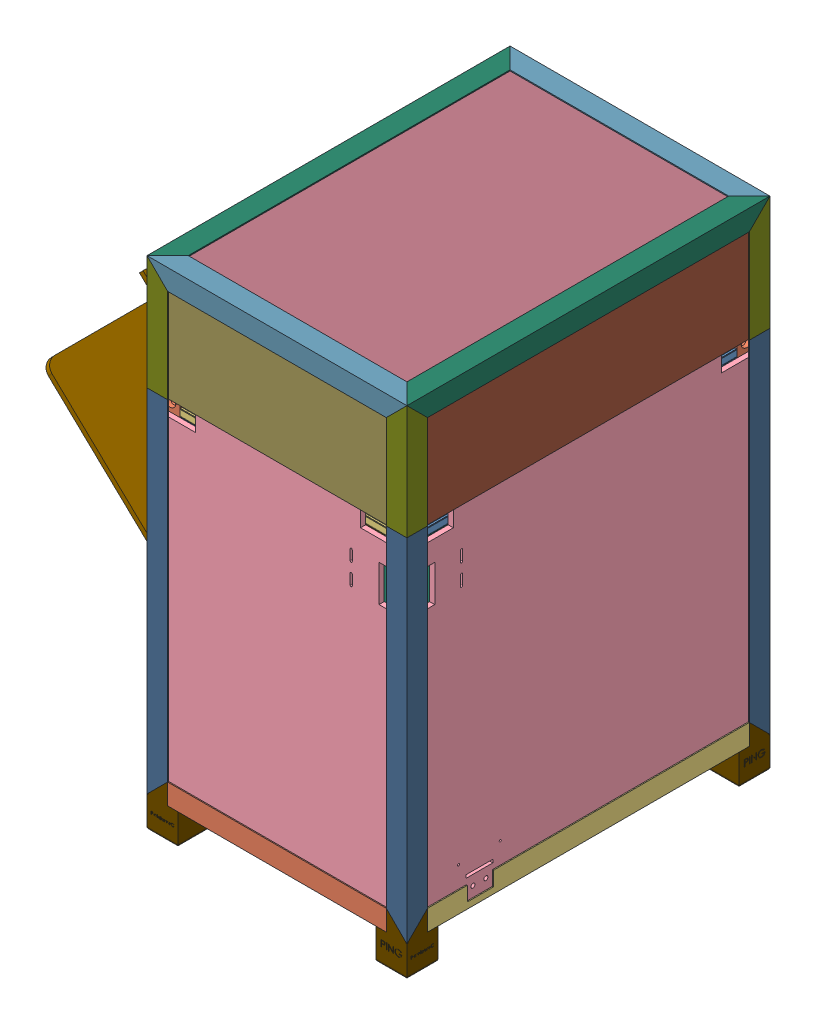
SolidWorks assembly carcasse, configuration Défaut. Lengths in mm.
Overall size (850.58 964 704).
62 component instances, 25 part files, 73 mates.
Components (placement in the parent):
- cadre_600x300mm-1: cadre_600x300mm [Défaut] at (-215.194 -19.8636 -400) size (480 40 680)
  - prof_40x40x600mm-1: prof_40x40x600mm [Défaut] at (-14.8937 4.0689 600) size (40 40 600)
  - Rexroth-Default-1: Rexroth-Default [Default] at (-14.8937 24.0689 720) x (0 -1 0) z (-1 0 0) size (40 40 40)
  - prof_40x40x600mm-3: prof_40x40x600mm [Défaut] at (425.1063 4.0689 600) size (40 40 600)
  - Rexroth-Default-3: Rexroth-Default [Default] at (-14.8937 24.0689 80) x (0 -1 0) z (0 0 -1) size (40 40 40)
  - Rexroth-Default-4: Rexroth-Default [Default] at (425.1063 24.0689 80) x (0 -1 0) z (1 0 0) size (40 40 40)
  - Rexroth-Default-5: Rexroth-Default [Default] at (425.1063 24.0689 720) x (0 -1 0) z (0 0 1) size (40 40 40)
  - prof_40x40x300mm-1: prof_40x40x300mm [Défaut] at (105.1063 4.0689 720) x (0 0 1) z (-1 0 0) size (40 40 400)
  - prof_40x40x300mm-2: prof_40x40x300mm [Défaut] at (105.1063 4.0689 80) x (0 0 1) z (-1 0 0) size (40 40 400)
- prof_40x40x600mm-1: prof_40x40x600mm [Défaut] at (209.9123 104.2053 -320) x (1 0 0) z (0 -1 0) size (40 40 600)
- prof_40x40x600mm-2: prof_40x40x600mm [Défaut] at (209.9123 104.2053 320) x (1 0 0) z (0 -1 0) size (40 40 600)
- prof_40x40x600mm-3: prof_40x40x600mm [Défaut] at (-230.0877 104.2053 320) x (1 0 0) z (0 -1 0) size (40 40 600)
- prof_40x40x600mm-4: prof_40x40x600mm [Défaut] at (-230.0877 104.2053 -320) x (1 0 0) z (0 -1 0) size (40 40 600)
- cadre_600x300mm-2: cadre_600x300mm [Défaut] at (195.0186 628.2742 -400) x (-1 0 0) z (0 0 1) size (480 40 680)
  - prof_40x40x600mm-1: prof_40x40x600mm [Défaut] at (-14.8937 4.0689 600) size (40 40 600)
  - Rexroth-Default-1: Rexroth-Default [Default] at (-14.8937 24.0689 720) x (0 -1 0) z (-1 0 0) size (40 40 40)
  - prof_40x40x600mm-3: prof_40x40x600mm [Défaut] at (425.1063 4.0689 600) size (40 40 600)
  - Rexroth-Default-3: Rexroth-Default [Default] at (-14.8937 24.0689 80) x (0 -1 0) z (0 0 -1) size (40 40 40)
  - Rexroth-Default-4: Rexroth-Default [Default] at (425.1063 24.0689 80) x (0 -1 0) z (1 0 0) size (40 40 40)
  - Rexroth-Default-5: Rexroth-Default [Default] at (425.1063 24.0689 720) x (0 -1 0) z (0 0 1) size (40 40 40)
  - prof_40x40x300mm-1: prof_40x40x300mm [Défaut] at (105.1063 4.0689 720) x (0 0 1) z (-1 0 0) size (40 40 400)
  - prof_40x40x300mm-2: prof_40x40x300mm [Défaut] at (105.1063 4.0689 80) x (0 0 1) z (-1 0 0) size (40 40 400)
- plaque_acrylique_680x670-2: plaque_acrylique_680x670 [Défaut] at (229.9123 299.2053 0) x (0 0 -1) z (1 0 0) size (680 670 10)
- plaque_acrylique_380x670_G-1: plaque_acrylique_380x670_G [Défaut] at (39.9123 299.2053 -350) size (480 670 10)
- plaque_acrylique_680x670_porte-1: plaque_acrylique_680x670_porte [Défaut] at (-260.0877 299.2053 0) x (0 0 -1) z (1 0 0) size (680 670 10)
- charniere-1: charniere [Défaut] at (-253.7309 154.2053 256.2875) x (0 0 1) z (0 -1 0) size (40 29.08 53.23)
  - axe charnière-1: axe charnière [Défaut] at (-76.2875 9.8568 0) size (40 5 5)
  - batant charnière-1: batant charnière [Défaut] at (-76.2875 10.1991 -17.6196) size (40 7 33.5)
  - batant charnière-2: batant charnière [Défaut] at (-36.2875 -2.6626 12.4029) x (-1 0 0) z (0 0.723942 -0.689861) size (40 7 33.5)
- charniere-2: charniere [Défaut] at (-253.7309 154.2053 -143.7125) x (0 0 1) z (0 -1 0) size (40 29.08 53.23)
  - axe charnière-1: axe charnière [Défaut] at (-76.2875 9.8568 0) size (40 5 5)
  - batant charnière-1: batant charnière [Défaut] at (-76.2875 10.1991 -17.6196) size (40 7 33.5)
  - batant charnière-2: batant charnière [Défaut] at (-36.2875 -2.6626 12.4029) x (-1 0 0) z (0 0.723942 -0.689861) size (40 7 33.5)
- porte-1: porte [Défaut] at (-366.1448 256.769 0) x (0 0 -1) z (0.689861 0.723942 0) size (480 480 10)
- eclisse_40x40x670_bisote_x1-1: eclisse_40x40x670_bisote_x1 [Défaut] at (-242.0877 -47.7947 -331.8864) size (40 682 40)
- eclisse_40x40x670_bisote_x1-2: eclisse_40x40x670_bisote_x1 [Défaut] at (-241.9741 -47.7947 332) x (0 0 -1) z (1 0 0) size (40 682 40)
- eclisse_40x40x670_bisote_x1-3: eclisse_40x40x670_bisote_x1 [Défaut] at (221.9123 -47.7947 331.8864) x (-1 0 0) z (0 0 -1) size (40 682 40)
- eclisse_40x40x670_bisote_x1-4: eclisse_40x40x670_bisote_x1 [Défaut] at (221.7986 -47.7947 -332) x (0 0 1) z (-1 0 0) size (40 682 40)
- couvercle-1: couvercle [Défaut] at (227.4119 747.9268 345) size (504 222 704)
  - plaque_acrylique_680x210-2: plaque_acrylique_680x210 [Défaut] at (-487.4996 -8.7215 -345) x (0 0 -1) z (1 0 0) size (680 210 10)
  - plaque_acrylique_380x210-2: plaque_acrylique_380x210 [Défaut] at (-187.4996 -8.7215 -695) size (480 210 10)
  - plaque_acrylique_380x680-1: plaque_acrylique_380x680 [Défaut] at (-187.4996 96.2785 -345) x (1 0 0) z (0 1 0) size (480 680 10)
  - eclisse_40x40x404_bisote_x2-1: eclisse_40x40x404_bisote_x2 [Défaut] at (14.5004 88.1649 -677) x (0 0 1) z (0 -1 0) size (40 504 40)
  - eclisse_40x40x704_bisote_x2-1: eclisse_40x40x704_bisote_x2 [Défaut] at (-5.6132 88.2785 -697) x (0 -1 0) z (-1 0 0) size (40 704 40)
  - eclisse_40x40x404_bisote_x2-2: eclisse_40x40x404_bisote_x2 [Défaut] at (-489.4996 88.1649 -13) x (0 0 -1) z (0 -1 0) size (40 504 40)
  - eclisse_40x40x704_bisote_x2-2: eclisse_40x40x704_bisote_x2 [Défaut] at (-469.4996 88.1649 -697) x (1 0 0) z (0 -1 0) size (40 704 40)
  - eclisse_40x40x222_bisote_x1-1: eclisse_40x40x222_bisote_x1 [Défaut] at (-469.386 108.2785 -677) x (0 0 1) z (1 0 0) size (40 222 40)
  - eclisse_40x40x222_bisote_x1-2: eclisse_40x40x222_bisote_x1 [Défaut] at (-5.4996 108.2785 -676.8864) x (-1 0 0) z (0 0 1) size (40 222 40)
  - eclisse_40x40x222_bisote_x1-4: eclisse_40x40x222_bisote_x1 [Défaut] at (-469.4996 108.2785 -13.1136) x (1 0 0) z (0 0 -1) size (40 222 40)
  - plaque_acrylique_380x210_Moteur-1: plaque_acrylique_380x210_Moteur [Défaut] at (-187.4996 -8.7215 -5) size (480 210 10)
  - plaque_acrylique_680x210_Moteur-1: plaque_acrylique_680x210_Moteur [Défaut] at (2.5004 -8.7215 -345) x (0 0 -1) z (1 0 0) size (680 210 10)
  - eclisse_40x40x222_bisote_x1_Moteur-1: eclisse_40x40x222_bisote_x1_Moteur [Défaut] at (-5.6132 108.2785 -13) x (0 0 -1) z (-1 0 0) size (40 222 40)
- plaque_acrylique_bas_380x680-1: plaque_acrylique_bas_380x680 [Défaut] at (39.9123 -35.7947 0) x (1 0 0) z (0 -1 0) size (480 680 10)
- Pied-1: Pied [Défaut] at (181.9123 -47.7947 -292) x (-1 0 0) z (0 -1 0) size (60 60 100)
- Pied-2: Pied [Défaut] at (181.9123 -47.7947 292) x (0 0 -1) z (0 -1 0) size (60 60 100)
- Pied-3: Pied [Défaut] at (-202.0877 -47.7947 292) x (1 0 0) z (0 -1 0) size (60 60 100)
- Pied-4: Pied [Défaut] at (-202.0877 -47.7947 -292) x (0 0 1) z (0 -1 0) size (60 60 100)
- eclisse_bas_40x40x704-2: eclisse_bas_40x40x704 [Défaut] at (-242.0877 -27.681 312) x (1 0 0) z (0 1 0) size (40 624 40)
- eclisse_bas_40x40x404-1: eclisse_bas_40x40x404 [Défaut] at (-222.0877 -27.681 -332) x (0 0 1) z (0 1 0) size (40 424 40)
- eclisse_bas_40x40x404-2: eclisse_bas_40x40x404 [Défaut] at (201.9123 -27.681 332) x (0 0 -1) z (0 1 0) size (40 424 40)
- eclisse_bas_support_Z_40x40x704-1: eclisse_bas_support_Z_40x40x704 [Défaut] at (221.7986 -27.7947 312) x (0 1 0) z (-1 0 0) size (40 624 40)
- plaque_acrylique_380x670_D-2: plaque_acrylique_380x670_D [Défaut] at (-60.0877 299.2053 350) x (-1 0 0) z (0 0 -1) size (480 670 10)
Mates (geometry in assembly coordinates):
- Coïncidente1: coincident anti-aligned: plane of cadre_600x300mm-1/Rexroth-Default-3 through (-230.0877 4.2053 -320) normal (0 1 0); plane of prof_40x40x600mm-4 through (-213.0877 4.2053 -337) normal (0 -1 0)
- Coïncidente2: coincident anti-aligned: plane of cadre_600x300mm-1/Rexroth-Default-1 through (-230.0877 4.2053 320) normal (0 1 0); plane of prof_40x40x600mm-3 through (-213.0877 4.2053 303) normal (0 -1 0)
- Coïncidente3: coincident anti-aligned: plane of cadre_600x300mm-1/Rexroth-Default-5 through (209.9123 4.2053 320) normal (0 1 0); plane of prof_40x40x600mm-2 through (226.9123 4.2053 303) normal (0 -1 0)
- Coïncidente4: coincident anti-aligned: plane of cadre_600x300mm-1/Rexroth-Default-4 through (209.9123 4.2053 -320) normal (0 1 0); plane of prof_40x40x600mm-1 through (226.9123 4.2053 -337) normal (0 -1 0)
- Coïncidente5: coincident aligned: plane of cadre_600x300mm-1/Rexroth-Default-4 through (229.9123 -15.7947 -320) normal (1 0 0); plane of prof_40x40x600mm-1 through (229.9123 604.2053 -314) normal (1 0 0)
- Coïncidente6: coincident aligned: plane of cadre_600x300mm-1/Rexroth-Default-4 through (209.9123 -15.7947 -340) normal (0 0 -1); plane of prof_40x40x600mm-1 through (215.9123 604.2053 -340) normal (0 0 -1)
- Coïncidente7: coincident aligned: plane of cadre_600x300mm-1/Rexroth-Default-5 through (229.9123 -15.7947 320) normal (1 0 0); plane of prof_40x40x600mm-2 through (229.9123 604.2053 303) normal (1 0 0)
- Coïncidente8: coincident aligned: plane of cadre_600x300mm-1/Rexroth-Default-5 through (209.9123 -15.7947 340) normal (0 0 1); plane of prof_40x40x600mm-2 through (226.9123 604.2053 340) normal (0 0 1)
- Coïncidente9: coincident aligned: plane of cadre_600x300mm-1/Rexroth-Default-1 through (-230.0877 -15.7947 340) normal (0 0 1); plane of prof_40x40x600mm-3 through (-213.0877 604.2053 340) normal (0 0 1)
- Coïncidente10: coincident aligned: plane of cadre_600x300mm-1/Rexroth-Default-1 through (-250.0877 -15.7947 320) normal (-1 0 0); plane of prof_40x40x600mm-3 through (-250.0877 604.2053 337) normal (-1 0 0)
- Coïncidente11: coincident aligned: plane of cadre_600x300mm-1/Rexroth-Default-3 through (-250.0877 -15.7947 -320) normal (-1 0 0); plane of prof_40x40x600mm-4 through (-250.0877 604.2053 -303) normal (-1 0 0)
- Coïncidente12: coincident aligned: plane of cadre_600x300mm-1/Rexroth-Default-3 through (-230.0877 -15.7947 -340) normal (0 0 -1); plane of prof_40x40x600mm-4 through (-247.0877 604.2053 -340) normal (0 0 -1)
- Coïncidente13: coincident anti-aligned: plane of prof_40x40x600mm-1 through (226.9123 604.2053 -337) normal (0 1 0); plane of cadre_600x300mm-2/Rexroth-Default-3 through (209.9123 604.2053 -320) normal (0 -1 0)
- Coïncidente14: coincident aligned: plane of prof_40x40x600mm-3 through (-250.0877 604.2053 337) normal (-1 0 0); plane of cadre_600x300mm-2/Rexroth-Default-5 through (-250.0877 624.2053 320) normal (-1 0 0)
- Coïncidente15: coincident aligned: plane of prof_40x40x600mm-3 through (-236.0877 604.2053 340) normal (0 0 1); plane of cadre_600x300mm-2/Rexroth-Default-5 through (-230.0877 624.2053 340) normal (0 0 1)
- Coïncidente38: coincident anti-aligned: plane of cadre_600x300mm-2/prof_40x40x600mm-1 through (229.9123 630.2053 -300) normal (1 0 0); plane of plaque_acrylique_680x670-2 through (229.9123 299.2053 0) normal (-1 0 0)
- Coïncidente39: coincident aligned: plane of prof_40x40x600mm-2 through (226.9123 604.2053 340) normal (0 0 1); plane of plaque_acrylique_680x670-2 through (239.9123 634.2053 340) normal (0 0 1)
- Coïncidente40: coincident aligned: plane of cadre_600x300mm-1/prof_40x40x600mm-3 through (215.9123 -35.7947 -300) normal (0 -1 0); plane of plaque_acrylique_680x670-2 through (239.9123 -35.7947 340) normal (0 -1 0)
- Coïncidente44: coincident aligned: plane of cadre_600x300mm-1/prof_40x40x300mm-2 through (189.9123 -35.7947 -337) normal (0 -1 0); plane of plaque_acrylique_380x670_G-1 through (-250.0877 -35.7947 -340) normal (0 -1 0)
- Coïncidente45: coincident aligned: plane of cadre_600x300mm-2/Rexroth-Default-4 through (-250.0877 624.2053 -320) normal (-1 0 0); plane of plaque_acrylique_380x670_G-1 through (-250.0877 634.2053 -340) normal (-1 0 0)
- Coïncidente46: coincident anti-aligned: plane of prof_40x40x600mm-4 through (-247.0877 604.2053 -340) normal (0 0 -1); plane of plaque_acrylique_380x670_G-1 through (39.9123 299.2053 -340) normal (0 0 1)
- Coïncidente48: coincident aligned: plane of cadre_600x300mm-2/Rexroth-Default-5 through (-230.0877 624.2053 340) normal (0 0 1); plane of plaque_acrylique_680x670_porte-1 through (-250.0877 634.2053 340) normal (0 0 1)
- Coïncidente50: coincident anti-aligned: plane of plaque_acrylique_680x670_porte-1 through (-260.0877 299.2053 0) normal (-1 0 0); plane of charniere-1/batant charnière-1 through (-260.0877 114.2053 220) normal (1 0 0)
- Coïncidente51: coincident anti-aligned: plane of plaque_acrylique_680x670_porte-1 through (-260.0877 299.2053 0) normal (-1 0 0); plane of charniere-2/batant charnière-1 through (-260.0877 114.2053 -180) normal (1 0 0)
- Distance4: distance = 20 mm anti-aligned: plane of charniere-2/batant charnière-1 through (-263.5877 154.2053 -220) normal (0 0 -1); plane of plaque_acrylique_680x670_porte-1 through (-260.0877 574.2053 -240) normal (0 0 1)
- Coïncidente54: coincident aligned: line of plaque_acrylique_680x670_porte-1 through (-260.0877 154.2053 220) axis (0 0 -1); line of charniere-2/batant charnière-1 through (-260.0877 154.2053 -180) axis (0 0 -1)
- Distance5: distance = 20 mm anti-aligned: plane of plaque_acrylique_680x670_porte-1 through (-260.0877 574.2053 240) normal (0 0 -1); plane of charniere-1/batant charnière-1 through (-263.5877 154.2053 220) normal (0 0 1)
- Coïncidente57: coincident aligned: line of plaque_acrylique_680x670_porte-1 through (-260.0877 154.2053 220) axis (0 0 -1); line of charniere-1/batant charnière-1 through (-260.0877 154.2053 220) axis (0 0 -1)
- Coïncidente62: coincident anti-aligned: plane of charniere-1/batant charnière-2 through (-290.1309 184.3336 180) normal (0.689861 0.723942 0); plane of porte-1 through (-586.947 467.1766 30) normal (-0.689861 -0.723942 0)
- Coïncidente63: coincident anti-aligned: line of charniere-1/batant charnière-2 through (-261.1732 156.7391 200) axis (0 0 1); line of porte-1 through (-261.1732 156.7391 220) axis (0 0 -1)
- Coïncidente64: coincident anti-aligned: plane of plaque_acrylique_680x670_porte-1 through (-260.0877 574.2053 240) normal (0 0 -1); plane of porte-1 through (-558.3301 453.7202 240) normal (0 0 1)
- Coïncidente65: coincident anti-aligned: plane of plaque_acrylique_380x670_G-1 through (39.9123 299.2053 -350) normal (0 0 -1); plane of eclisse_40x40x670_bisote_x1-1 through (-260.0877 634.2053 -350) normal (0 0 1)
- Coïncidente66: coincident anti-aligned: plane of plaque_acrylique_680x670_porte-1 through (-260.0877 299.2053 0) normal (-1 0 0); plane of eclisse_40x40x670_bisote_x1-1 through (-260.0877 634.2053 -350) normal (1 0 0)
- Coïncidente67: coincident aligned: plane of plaque_acrylique_680x670_porte-1 through (-250.0877 634.2053 340) normal (0 1 0); plane of eclisse_40x40x670_bisote_x1-1 through (-242.0877 634.2053 -331.8864) normal (0 1 0)
- Coïncidente68: coincident anti-aligned: plane of plaque_acrylique_680x670-2 through (239.9123 299.2053 0) normal (1 0 0); plane of eclisse_40x40x670_bisote_x1-4 through (239.9123 634.2053 -350) normal (-1 0 0)
- Coïncidente69: coincident anti-aligned: plane of plaque_acrylique_380x670_G-1 through (39.9123 299.2053 -350) normal (0 0 -1); plane of eclisse_40x40x670_bisote_x1-4 through (239.9123 634.2053 -350) normal (0 0 1)
- Coïncidente70: coincident aligned: plane of plaque_acrylique_380x670_G-1 through (-250.0877 634.2053 -340) normal (0 1 0); plane of eclisse_40x40x670_bisote_x1-4 through (221.7986 634.2053 -332) normal (0 1 0)
- Coïncidente72: coincident anti-aligned: plane of plaque_acrylique_680x670_porte-1 through (-260.0877 299.2053 0) normal (-1 0 0); plane of eclisse_40x40x670_bisote_x1-2 through (-260.0877 634.2053 350) normal (1 0 0)
- Coïncidente74: coincident anti-aligned: plane of plaque_acrylique_680x670-2 through (239.9123 299.2053 0) normal (1 0 0); plane of eclisse_40x40x670_bisote_x1-3 through (239.9123 634.2053 350) normal (-1 0 0)
- Coïncidente100: coincident: plane of plaque_acrylique_680x670_porte-1 through (-250.0877 634.2053 340) normal (0 1 0); line of eclisse_40x40x670_bisote_x1-2 through (-260.0877 634.2053 350) axis (0 0 -1)
- Coïncidente101: coincident anti-aligned: plane of prof_40x40x600mm-4 through (-250.0877 604.2053 -326) normal (-1 0 0); plane of plaque_acrylique_680x670_porte-1 through (-250.0877 299.2053 0) normal (1 0 0)
- Coïncidente116: coincident anti-aligned: line of plaque_acrylique_680x670-2 through (239.9123 634.2053 -260) axis (0 0 1); line of couvercle-1/plaque_acrylique_680x210_Moteur-1 through (239.9123 634.2053 340) axis (0 0 -1)
- Coïncidente117: coincident anti-aligned: line of plaque_acrylique_380x670_G-1 through (149.9123 634.2053 -350) axis (-1 0 0); line of couvercle-1/plaque_acrylique_380x210-2 through (-170.0877 634.2053 -350) axis (1 0 0)
- Coïncidente118: coincident anti-aligned: plane of cadre_600x300mm-1/prof_40x40x600mm-1 through (-247.0877 -35.7947 -300) normal (0 -1 0); plane of plaque_acrylique_bas_380x680-1 through (39.9123 -35.7947 0) normal (0 1 0)
- Coïncidente119: coincident: plane of cadre_600x300mm-1/prof_40x40x600mm-1 through (-250.0877 -21.7947 -300) normal (-1 0 0); line of plaque_acrylique_bas_380x680-1 through (-250.0877 -35.7947 340) axis (0 0 -1)
- Coïncidente120: coincident: line of cadre_600x300mm-1/prof_40x40x300mm-2 through (189.9123 -32.7947 -340) axis (-1 0 0); plane of plaque_acrylique_bas_380x680-1 through (-250.0877 -45.7947 -340) normal (0 0 -1)
- Coaxiale1: concentric aligned: cylinder of plaque_acrylique_bas_380x680-1 through (209.9123 -35.7947 -320) axis (0 -1 0) radius 12.5; cylinder of Pied-1 through (209.9123 -27.7947 -320) axis (0 -1 0) radius 12
- Coïncidente124: coincident anti-aligned: plane of eclisse_40x40x670_bisote_x1-4 through (-348.0877 -47.7947 -352) normal (0 -0.707107 0.707107); plane of Pied-1 through (239.9123 -7.7947 -312) normal (0 0.707107 -0.707107)
- Coaxiale2: concentric aligned: circle of plaque_acrylique_bas_380x680-1; cylinder of Pied-2 through (209.9123 -27.7947 320) axis (0 -1 0) radius 12
- Coïncidente126: coincident anti-aligned: plane of eclisse_40x40x670_bisote_x1-3 through (241.9123 -47.7947 -238) normal (-0.707107 -0.707107 0); plane of Pied-2 through (201.9123 -7.7947 350) normal (0.707107 0.707107 0)
- Coaxiale3: concentric aligned: circle of plaque_acrylique_bas_380x680-1; cylinder of Pied-3 through (-230.0877 -27.7947 320) axis (0 -1 0) radius 12
- Coïncidente130: coincident anti-aligned: plane of eclisse_40x40x670_bisote_x1-2 through (327.9123 -47.7947 352) normal (0 -0.707107 -0.707107); plane of Pied-3 through (-260.0877 -7.7947 312) normal (0 0.707107 0.707107)
- Coaxiale4: concentric aligned: circle of plaque_acrylique_bas_380x680-1; cylinder of Pied-4 through (-230.0877 -27.7947 -320) axis (0 -1 0) radius 12
- Coïncidente131: coincident anti-aligned: plane of eclisse_40x40x670_bisote_x1-1 through (-262.0877 -47.7947 238) normal (0.707107 -0.707107 0); plane of Pied-4 through (-222.0877 -7.7947 -350) normal (-0.707107 0.707107 0)
- Coïncidente132: coincident anti-aligned: plane of plaque_acrylique_680x670_porte-1 through (-260.0877 299.2053 0) normal (-1 0 0); plane of eclisse_bas_40x40x704-2 through (-260.0877 -45.7947 -312) normal (1 0 0)
- Coïncidente133: coincident anti-aligned: plane of plaque_acrylique_bas_380x680-1 through (39.9123 -45.7947 0) normal (0 -1 0); plane of eclisse_bas_40x40x704-2 through (-260.0877 -45.7947 -312) normal (0 1 0)
- Coïncidente134: coincident anti-aligned: line of eclisse_40x40x670_bisote_x1-2 through (-262.0877 634.2053 312) axis (0 -1 0); line of eclisse_bas_40x40x704-2 through (-262.0877 -47.7947 312) axis (0 1 0)
- Coïncidente135: coincident anti-aligned: plane of plaque_acrylique_380x670_G-1 through (39.9123 299.2053 -350) normal (0 0 -1); plane of eclisse_bas_40x40x404-1 through (201.9123 -45.7947 -350) normal (0 0 1)
- Coïncidente136: coincident anti-aligned: plane of plaque_acrylique_bas_380x680-1 through (39.9123 -45.7947 0) normal (0 -1 0); plane of eclisse_bas_40x40x404-1 through (201.9123 -45.7947 -350) normal (0 1 0)
- Coïncidente137: coincident anti-aligned: line of Pied-1 through (201.9123 -7.7947 -352) axis (0 -1 0); line of eclisse_bas_40x40x404-1 through (201.9123 -47.7947 -352) axis (0 1 0)
- Coïncidente139: coincident anti-aligned: plane of plaque_acrylique_bas_380x680-1 through (39.9123 -45.7947 0) normal (0 -1 0); plane of eclisse_bas_40x40x404-2 through (-222.0877 -45.7947 350) normal (0 1 0)
- Coïncidente140: coincident anti-aligned: line of Pied-3 through (-222.0877 -7.7947 352) axis (0 -1 0); line of eclisse_bas_40x40x404-2 through (-222.0877 -47.7947 352) axis (0 1 0)
- Coïncidente142: coincident anti-aligned: plane of plaque_acrylique_680x670-2 through (239.9123 299.2053 0) normal (1 0 0); plane of eclisse_bas_support_Z_40x40x704-1 through (239.9123 -45.7947 -312) normal (-1 0 0)
- Coïncidente143: coincident anti-aligned: plane of plaque_acrylique_bas_380x680-1 through (39.9123 -45.7947 0) normal (0 -1 0); plane of eclisse_bas_support_Z_40x40x704-1 through (239.9123 -45.7947 -312) normal (0 1 0)
- Coïncidente144: coincident anti-aligned: plane of Pied-2 through (239.9123 -7.7947 312) normal (0 0 -1); plane of eclisse_bas_support_Z_40x40x704-1 through (221.7986 -27.7947 312) normal (0 0 1)
- Coïncidente151: coincident anti-aligned: plane of Pied-3 through (-202.0877 -47.7947 292) normal (0 1 0); plane of eclisse_bas_40x40x404-2 through (-222.0877 -47.7947 352) normal (0 -1 0)
- Coïncidente152: coincident anti-aligned: plane of Pied-2 through (181.9123 -47.7947 292) normal (0 1 0); plane of eclisse_bas_40x40x404-2 through (-222.0877 -47.7947 352) normal (0 -1 0)
- Coïncidente153: coincident anti-aligned: plane of cadre_600x300mm-2/Rexroth-Default-1 through (209.9123 624.2053 340) normal (0 0 1); plane of plaque_acrylique_380x670_D-2 through (-60.0877 299.2053 340) normal (0 0 -1)
- Coïncidente154: coincident aligned: plane of prof_40x40x600mm-3 through (-250.0877 604.2053 314) normal (-1 0 0); plane of plaque_acrylique_380x670_D-2 through (-250.0877 634.2053 340) normal (-1 0 0)
- Coïncidente155: coincident aligned: plane of cadre_600x300mm-1/prof_40x40x300mm-1 through (189.9123 -35.7947 303) normal (0 -1 0); plane of plaque_acrylique_380x670_D-2 through (229.9123 -35.7947 340) normal (0 -1 0)
- Coïncidente156: coincident anti-aligned: plane of eclisse_bas_40x40x404-2 through (-222.0877 -45.7947 350) normal (0 0 -1); plane of plaque_acrylique_380x670_D-2 through (-60.0877 299.2053 350) normal (0 0 1)
- Coïncidente157: coincident anti-aligned: plane of eclisse_40x40x670_bisote_x1-2 through (-260.0877 634.2053 350) normal (0 0 -1); plane of plaque_acrylique_380x670_D-2 through (-60.0877 299.2053 350) normal (0 0 1)
- Coïncidente158: coincident anti-aligned: plane of eclisse_40x40x670_bisote_x1-3 through (239.9123 634.2053 350) normal (0 0 -1); plane of plaque_acrylique_380x670_D-2 through (-60.0877 299.2053 350) normal (0 0 1)
